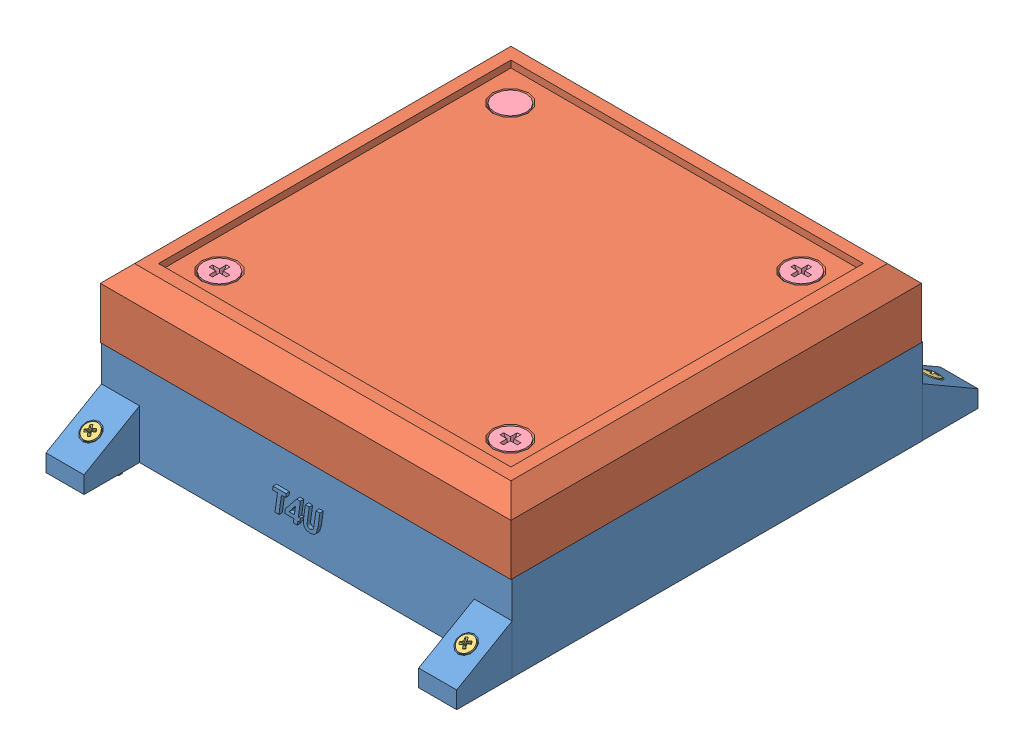
SolidWorks assembly SMT_CASE, configuration Default. Lengths in mm.
Overall size (275.62 52 287.3).
10 component instances, 4 part files, 10 mates.
Components (placement in the parent):
- BASE_CASE-1: BASE_CASE [Default] at (-59.6045 -58.9352 36.1932) size (275.62 25 287.3)
- TOP_CASE-1: TOP_CASE [Default] at (-20.8555 -13.9352 4.2258) x (-1 0 0) z (0 0 1) size (120 25 120)
- oval head_am-1: oval head_am [B18.6.7M - M2.5 x 0.45 x 16 Type I Cross Recessed OHMS --16N] at (-0.0395 -48.6471 99.6164) x (0 -0.866025 -0.5) z (0.5 -0.433013 0.75) size (16.58 4.7 4.7)
- oval head_am-2: oval head_am [B18.6.7M - M2.5 x 0.45 x 16 Type I Cross Recessed OHMS --16N] at (-109.0343 -49.0373 100.2921) x (0 -0.866025 -0.5) z (0.5 -0.433013 0.75) size (16.58 4.7 4.7)
- oval head_am-3: oval head_am [B18.6.7M - M2.5 x 0.45 x 16 Type I Cross Recessed OHMS --16N] at (-0.6111 -49.0805 -37.6504) x (0 -0.866025 0.5) z (0.5 0.433013 0.75) size (16.58 4.7 4.7)
- oval head_am-4: oval head_am [B18.6.7M - M2.5 x 0.45 x 16 Type I Cross Recessed OHMS --16N] at (-109.0563 -48.7815 -37.1325) x (0 -0.866025 0.5) z (0.5 0.433013 0.75) size (16.58 4.7 4.7)
- flat head screw_am_SMT-1: flat head screw_am_SMT [B18.6.7M - M5 x 0.8 x 50 Type I Cross Recessed FHMS --50N] at (-97.2987 -15.9352 74.1734) x (0 -1 0) z (0 0 1) size (50 9.3 9.3)
- flat head screw_am_SMT-2: flat head screw_am_SMT [B18.6.7M - M5 x 0.8 x 50 Type I Cross Recessed FHMS --50N] at (-12.2933 -15.9352 74.1352) x (0 -1 0) z (0 0 1) size (50 9.3 9.3)
- flat head screw_am_SMT-3: flat head screw_am_SMT [B18.6.7M - M5 x 0.8 x 50 Type I Cross Recessed FHMS --50N] at (-12.2933 -15.9352 -10.8648) x (0 -1 0) z (0 0 1) size (50 9.3 9.3)
- flat head screw_am_SMT-4: flat head screw_am_SMT [PreviewCfg] at (-97.2933 -15.9352 -10.8648) x (0 -1 0) z (0 0 1) size (50 9.3 9.3)
Mates (geometry in assembly coordinates):
- Coincident1: coincident: plane of BASE_CASE-1 through (-59.6045 -33.9352 36.1932) normal (0 1 0); plane of TOP_CASE-1 through (-20.8555 -33.9352 4.2258) normal (0 -1 0)
- Coincident2: coincident: line of BASE_CASE-1 through (-114.5732 -33.9352 -28.6417) axis (0 0 1); line of TOP_CASE-1 through (-114.5732 -33.9352 -28.2904) axis (0 0 1)
- Coincident21: coincident: cone of BASE_CASE-1 through (-0.0395 -49.1669 99.3163) axis (0 -0.866025 -0.5); cone of oval head_am-1 through (-0.0395 -50.466 98.5663) axis (0 -0.866025 -0.5)
- Coincident22: coincident: cone of BASE_CASE-1 through (-109.0343 -49.5571 99.992) axis (0 -0.866025 -0.5); cone of oval head_am-2 through (-109.0343 -50.8561 99.242) axis (0 -0.866025 -0.5)
- Coincident23: coincident: cone of BASE_CASE-1 through (-0.6111 -49.6003 -37.3503) axis (0 -0.866025 0.5); cone of oval head_am-3 through (-0.6111 -50.8994 -36.6003) axis (0 -0.866025 0.5)
- Coincident24: coincident: cone of BASE_CASE-1 through (-109.0563 -49.3013 -36.8324) axis (0 -0.866025 0.5); cone of oval head_am-4 through (-109.0563 -50.6003 -36.0824) axis (0 -0.866025 0.5)
- Coincident37: coincident: cone of TOP_CASE-1 through (-97.2987 -15.9352 74.1734) axis (0 -1 0); cone of flat head screw_am-1 through (-97.2987 -16.4852 74.1734) axis (0 -1 0)
- Coincident38: coincident: cone of TOP_CASE-1 through (-12.2933 -15.9352 74.1352) axis (0 -1 0); cone of flat head screw_am-2 through (-12.2933 -16.4852 74.1352) axis (0 -1 0)
- Coincident39: coincident: cone of TOP_CASE-1 through (-12.2933 -15.9352 -10.8648) axis (0 -1 0); cone of flat head screw_am-3 through (-12.2933 -16.4852 -10.8648) axis (0 -1 0)
- Coincident40: coincident: cone of TOP_CASE-1 through (-97.2933 -15.9352 -10.8648) axis (0 -1 0); cone of flat head screw_am-4 through (-97.2933 -16.4852 -10.8648) axis (0 -1 0)
